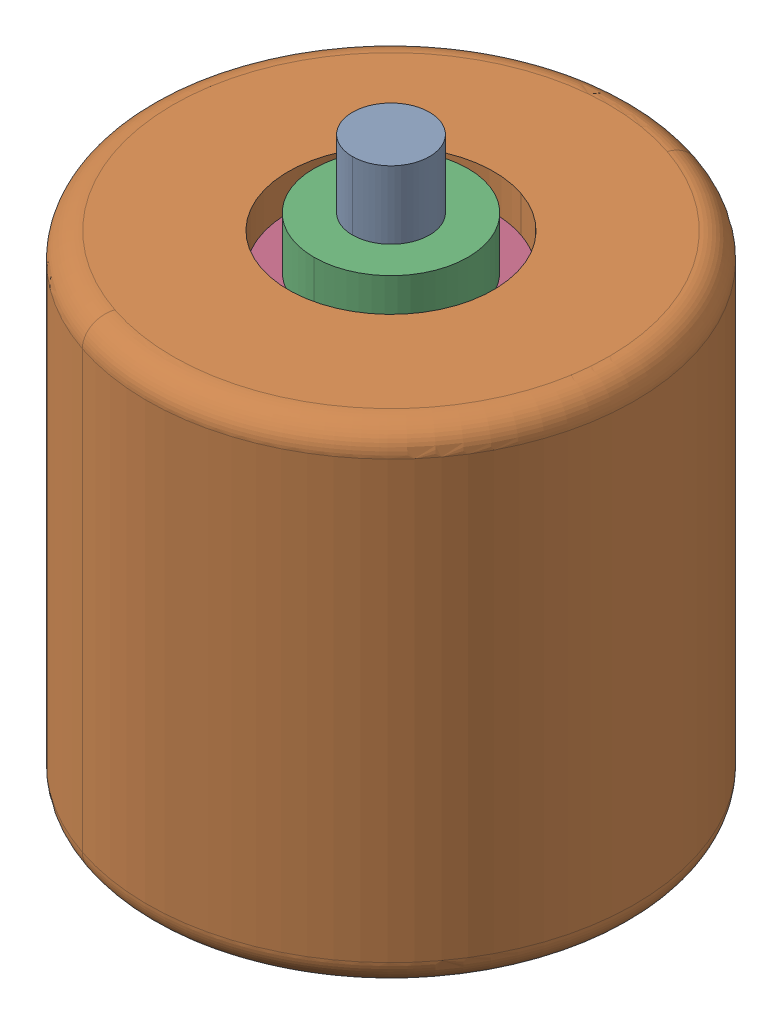
SolidWorks assembly 南京理工大学Alliance航发小滚子装配.STEP, configuration 默认. Lengths in mm.
Overall size (24.07 25.5 24.07).
6 component instances, 4 part files, 0 mates.
Components (placement in the parent):
- 南京理工大学Alliance销钉M3x25.5.STEP-1: 南京理工大学Alliance销钉M3x25.5.STEP [默认] at origin size (3 25.5 3)
- 南京理工大学Alliance白色滚子.STEP-1: 南京理工大学Alliance白色滚子.STEP [默认] at (0 3.25 0) x (0.94776 0 0.318984) z (-0.318984 0 0.94776) size (19 19 19)
- 南京理工大学Alliance垫片3x6x2.STEP-1: 南京理工大学Alliance垫片3x6x2.STEP [默认] at (0 20.85 0) size (6 2 6)
- 南京理工大学Alliance轴承3x8x4.STEP-1: 南京理工大学Alliance轴承3x8x4.STEP [默认] at (0 16.85 0) size (8 4 8)
- 南京理工大学Alliance轴承3x8x4.STEP-2: 南京理工大学Alliance轴承3x8x4.STEP [默认] at (0 4.65 0) size (8 4 8)
- 南京理工大学Alliance垫片3x6x2.STEP-2: 南京理工大学Alliance垫片3x6x2.STEP [默认] at (0 2.65 0) size (6 2 6)
